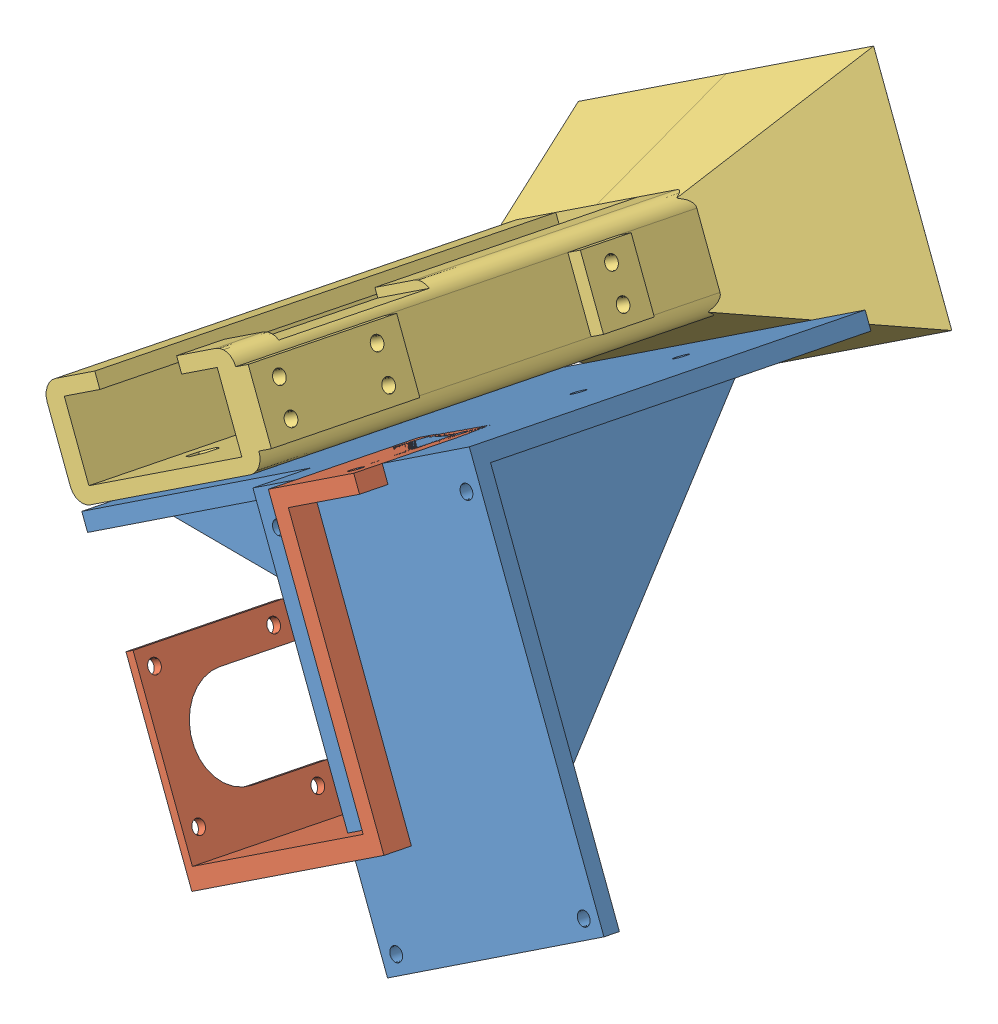
SolidWorks assembly Assem1, configuration Default. Lengths in mm.
Overall size (197.6 161.46 202.98).
4 component instances, 4 part files, 4 mates.
Components (placement in the parent):
- asemb2-1: asemb2 [Default] at (77.6136 16.3596 -52.0701)
- tianHolder-1: tianHolder [Default] at (12.3578 88.1822 113.9227) x (0.843057 0.530586 -0.087941) z (-0.014262 0.18551 0.982539) size (123.5 93 102.5)
- motorholder33-1: motorholder33 [Default] at (-14.6829 11.5813 121.1367) x (0.842807 0.5329 -0.075453) z (-0.02497 0.178755 0.983577) size (74 70 38.5)
- trumpgear2-1: trumpgear2 [Default] at (-30.755 47.6358 -22.4266) x (-0.842807 -0.5329 0.075453) z (0.537636 -0.827082 0.163963) size (83 156.63 54)
Mates (geometry in assembly coordinates):
- Coincident2: coincident anti-aligned: plane of tianHolder-1 through (12.4148 87.4401 109.9925) normal (-0.537636 0.827082 -0.163963); plane of trumpgear2-1 through (-4.9155 72.9258 93.6035) normal (0.537636 -0.827082 0.163963)
- Coincident3: coincident: plane of motorholder33-1 through (24.5077 36.3612 117.6281) normal (-0.842807 -0.5329 0.075453); plane of trumpgear2-1 through (-5.4708 63.6228 -24.6902) normal (0.842807 0.5329 -0.075453)
- Parallel1: parallel: plane of tianHolder-1 through (12.4148 87.4401 109.9925) normal (-0.537636 0.827082 -0.163963); line of trumpgear2-1 through (-9.3301 85.177 -67.9805) axis (-0.842807 -0.5329 0.075453)
- Coincident5: coincident aligned: plane of tianHolder-1 through (12.4148 87.4401 109.9925) normal (-0.537636 0.827082 -0.163963); plane of motorholder33-1 through (22.1703 95.7149 119.7447) normal (-0.537636 0.827082 -0.163963)
